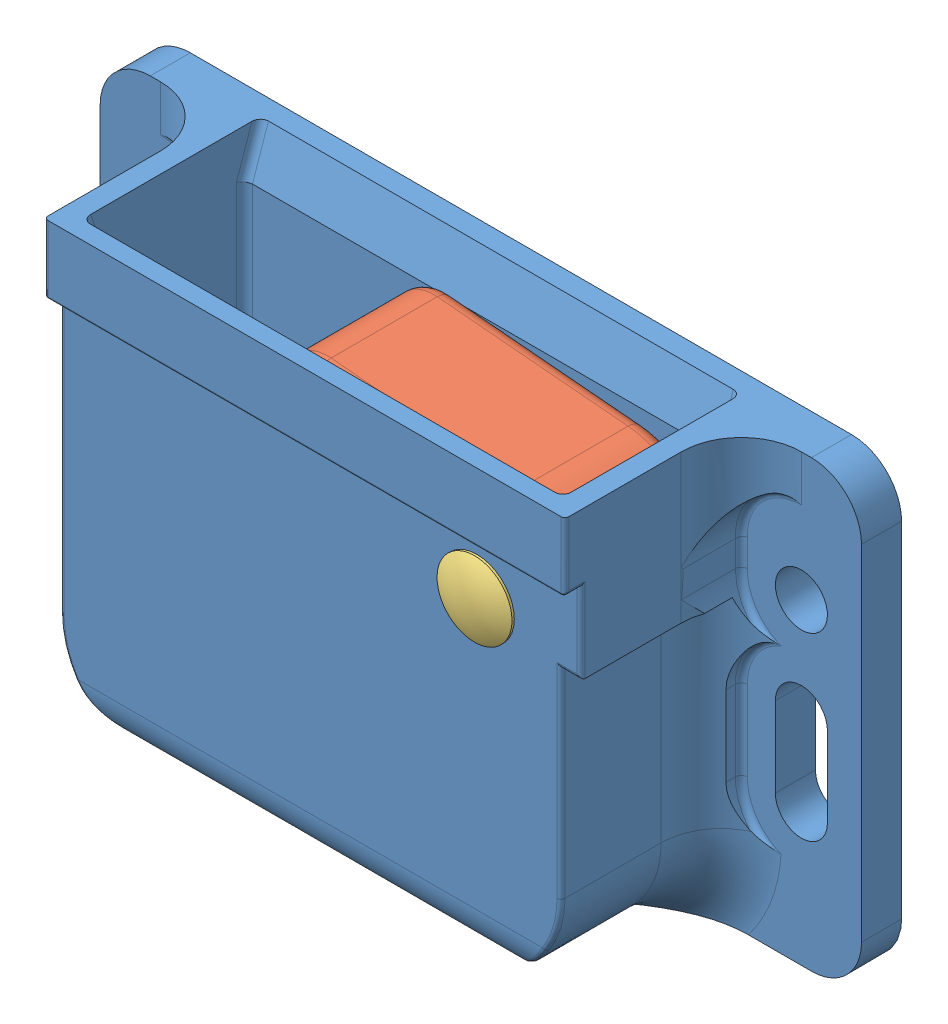
SolidWorks assembly SW3dPS-C3-810, configuration Default. Lengths in mm.
Overall size (48.27 28.42 13.73).
4 component instances, 3 part files, 0 mates.
Components (placement in the parent):
- SW3dPS-C3-810_C3_Grabber_Door_Catch_clf-1: SW3dPS-C3-810_C3_Grabber_Door_Catch_clf [Default] at origin size (48.27 28.42 13.73)
  - SW3dPS-C3-810_c3_housing_clf-1: SW3dPS-C3-810_c3_housing_clf [Default] at origin size (48.27 28.42 13.73)
  - SW3dPS-C3-810_C3_Pawl_Clf-1: SW3dPS-C3-810_C3_Pawl_Clf [Default] at (-1.6193 3.0428 -9.271) x (0.996195 -0.087156 0) z (0 0 1) size (18.2 16.64 9.27)
  - SW3dPS-C3-810_c3_rivet_clf-1: SW3dPS-C3-810_c3_rivet_clf [Default] at origin size (4.75 4.75 12.92)
